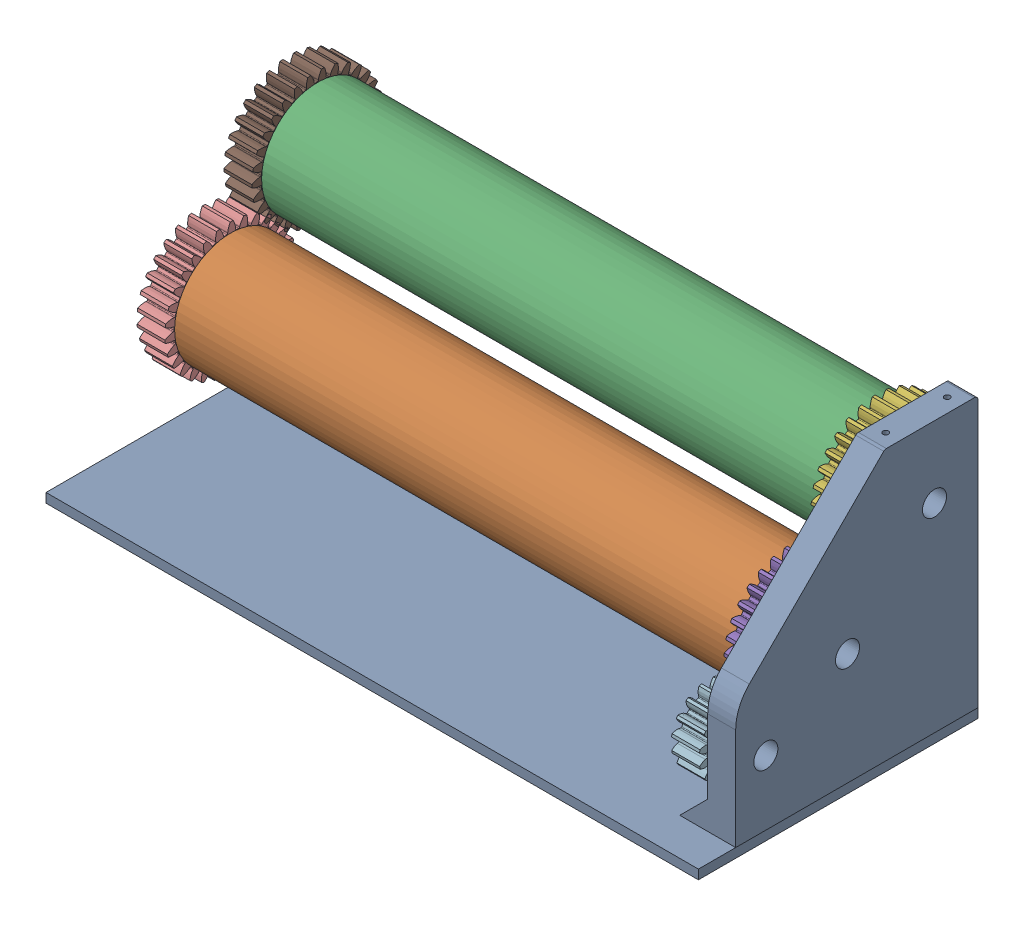
SolidWorks assembly SheetMaker, configuration Default. Lengths in mm.
Overall size (346 155.63 160.52).
13 component instances, 6 part files, 34 mates.
Components (placement in the parent):
- Base-1: Base [Default] at origin size (350 5 150) (hidden)
- Tube_60-1: Tube_60 [Default] at (-156 65 -5) x (0 -0.814129 0.580684) z (1 0 0) size (60 60 300)
- Tube_60-2: Tube_60 [Default] at (144 111.669 -51.669) x (0 -0.107637 0.99419) z (-1 0 0) size (60 60 300)
- Shaft-1: Shaft [Default] at (129 65 -5) x (0 0.66263 -0.748947) z (0 -0.748947 -0.66263) size (52 45 52)
- Gear_slave-3: Gear_slave [Default] at (151.5 65 -5) x (0 -0.979922 -0.199381) z (1 0 0) size (70.33 70.39 15)
- Gear_slave-4: Gear_slave [Default] at (151.5 111.669 -51.669) x (0 -0.821391 -0.570366) z (1 0 0) size (70.33 70.39 15)
- Shaft-2: Shaft [Default] at (129 111.669 -51.669) x (0 0.821391 0.570366) z (0 0.570366 -0.821391) size (52 45 52)
- Shaft-3: Shaft [Default] at (-141 65 -5) x (0 0.15255 -0.988296) z (0 0.988296 0.15255) size (52 45 52)
- Shaft-4: Shaft [Default] at (-141 111.669 -51.669) x (0 -0.799243 0.601008) z (0 -0.601008 -0.799243) size (52 45 52)
- Gear_slave-5: Gear_slave [Default] at (-163.5 65 -5) x (0 0.779614 0.62626) z (-1 0 0) size (70.33 70.39 15)
- Gear_slave-6: Gear_slave [Default] at (-163.5 111.669 -51.669) x (0 -0.92011 -0.391661) z (-1 0 0) size (70.33 70.39 15)
- Gear_master-3: Gear_master [Default] at (151.5 39.7 38.8209) x (0 0.997608 -0.069128) z (-1 0 0) size (39.49 39.49 15)
- Side_1-1: Side_1 [Default] at (160 5 55) x (0 0 -1) z (1 0 0) size (130 145 30)
Mates (geometry in assembly coordinates):
- Coincident2: coincident: plane of Tube_60-1 through (144 65 -5) normal (1 0 0); plane of Gear_master-1 through (165 85 52.8629) normal (-1 0 0)
- Concentric1: concentric: cylinder of Tube_60-1 through (144 65 -5) axis (-1 0 0) radius 30; circle of Gear_slave-1
- Coincident5: coincident aligned: plane of Tube_60-1 through (144 65 -5) normal (1 0 0); plane of Tube_60-2 through (144 111.669 -51.669) normal (1 0 0)
- Coincident4: coincident anti-aligned: plane of Tube_60-2 through (144 111.669 -51.669) normal (1 0 0); plane of Gear_master-2 through (165 85 -13.1371) normal (-1 0 0)
- Concentric2: concentric aligned: cylinder of Tube_60-2 through (-156 111.669 -51.669) axis (1 0 0) radius 30; circle of Gear_slave-2
- Concentric3: concentric aligned: cylinder of Tube_60-1 through (144 65 -5) axis (-1 0 0) radius 25.5; cylinder of Shaft-1 through (144 65 -5) axis (-1 0 0) radius 26
- Coincident6: coincident: line of Gear_master-1 through (165 82.8222 58.2099) axis (0 -0.613444 -0.789738); line of Shaft-1 through (144 70.4957 11.4255) axis (0 0.66263 -0.748947)
- Coincident7: coincident aligned: line of Shaft-1 through (144 48.0273 -8.4534) axis (0 0.66263 -0.748947); line of Gear_slave-3 through (144 48.0273 -8.4534) axis (0 0.66263 -0.748947)
- Coincident8: coincident aligned: line of Shaft-1 through (144 76.4771 -17.9721) axis (0 0.317292 0.948328); line of Gear_slave-3 through (144 76.4771 -17.9721) axis (0 0.317292 0.948328)
- Coincident9: coincident anti-aligned: plane of Tube_60-1 through (144 65 -5) normal (1 0 0); plane of Gear_slave-3 through (144 65 -5) normal (-1 0 0)
- Concentric4: concentric anti-aligned: cylinder of Tube_60-2 through (-156 111.669 -51.669) axis (1 0 0) radius 25.5; cylinder of Shaft-2 through (144 111.669 -51.669) axis (-1 0 0) radius 26
- Coincident10: coincident aligned: line of Gear_slave-4 through (144 96.0001 -44.2877) axis (0 0.083256 -0.996528); line of Shaft-2 through (144 96.0001 -44.2877) axis (0 0.083256 -0.996528)
- Coincident11: coincident aligned: line of Gear_slave-4 through (144 110.227 -34.4087) axis (0 -0.821391 -0.570366); line of Shaft-2 through (144 110.227 -34.4087) axis (0 -0.821391 -0.570366)
- Coincident12: coincident anti-aligned: plane of Tube_60-2 through (144 111.669 -51.669) normal (1 0 0); plane of Gear_slave-4 through (144 111.669 -51.669) normal (-1 0 0)
- Concentric5: concentric anti-aligned: cylinder of Tube_60-1 through (144 65 -5) axis (-1 0 0) radius 25.5; cylinder of Shaft-3 through (-156 65 -5) axis (1 0 0) radius 26
- Concentric6: concentric aligned: cylinder of Tube_60-2 through (-156 111.669 -51.669) axis (1 0 0) radius 25.5; cylinder of Shaft-4 through (-156 111.669 -51.669) axis (1 0 0) radius 26
- Coincident13: coincident aligned: line of Shaft-4 through (-156 127.6058 -44.8853) axis (0 -0.120867 -0.992669); line of Gear_slave-6 through (-156 127.6058 -44.8853) axis (0 -0.120867 -0.992669)
- Coincident14: coincident aligned: line of Shaft-4 through (-156 125.5123 -62.0788) axis (0 -0.92011 -0.391661); line of Gear_slave-6 through (-156 125.5123 -62.0788) axis (0 -0.92011 -0.391661)
- Coincident15: coincident aligned: line of Shaft-3 through (-156 67.6422 -22.1178) axis (0 -0.932164 0.362036); line of Gear_slave-5 through (-156 67.6422 -22.1178) axis (0 -0.932164 0.362036)
- Coincident16: coincident aligned: line of Shaft-3 through (-156 81.1456 -11.2706) axis (0 -0.779614 -0.62626); line of Gear_slave-5 through (-156 81.1456 -11.2706) axis (0 -0.779614 -0.62626)
- Coincident17: coincident anti-aligned: plane of Tube_60-1 through (-156 65 -5) normal (-1 0 0); plane of Gear_slave-5 through (-156 65 -5) normal (1 0 0)
- Coincident18: coincident anti-aligned: plane of Tube_60-2 through (-156 111.669 -51.669) normal (-1 0 0); plane of Gear_slave-6 through (-156 111.669 -51.669) normal (1 0 0)
- InPlace1: in place: plane of Base-1 through (0 5 0) normal (0 1 0); plane of ? through (0 5 0) normal (0 1 0); moOrthogonalPlaneRef_w of Base-1 through (0 5 0) normal (0 1 0); plane of ? through (0 5 0) normal (0 0 -1); plane of Base-1 through (0 5 0) normal (0 1 0); plane of ? through (0 5 0) normal (1 0 0); plane of Base-1 through (0 5 0) normal (0 1 0); unknown of ?
- Coincident20: coincident aligned: plane of Base-1; plane of ?
- Coincident21: coincident aligned: moOrthogonalPlaneRef_w of Base-1 through (0 5 0) normal (0 0 -1); plane of Part1^SheetMaker-1 through (0 5 0) normal (0 0 -1)
- Coincident22: coincident anti-aligned: moOrthogonalPlaneRef_w of Base-1 through (0 5 0) normal (-1 0 0); plane of Part1^SheetMaker-1 through (0 5 0) normal (1 0 0)
- Coincident23: coincident anti-aligned: plane of Base-1 through (0 5 0) normal (0 1 0); plane of Side_1-1 through (175 5 55) normal (0 -1 0)
- Coincident24: coincident aligned: line of Base-1 through (175 5 75) axis (0 0 -1); line of Side_1-1 through (175 5 55) axis (0 0 -1)
- Coincident25: coincident aligned: plane of Base-1 through (175 5 -75) normal (0 0 -1); plane of Side_1-1 through (175 5 -75) normal (0 0 -1)
- Concentric9: concentric anti-aligned: cylinder of Shaft-1 through (141 65 -5) axis (1 0 0) radius 3.25; cylinder of Side_1-1 through (175 65 -5) axis (-1 0 0) radius 6.45
- Distance1: distance = 1 mm anti-aligned: plane of Shaft-1 through (159 65 -5) normal (1 0 0); plane of Side_1-1 through (160 5 55) normal (-1 0 0)
- Concentric10: concentric anti-aligned: cylinder of Shaft-2 through (141 111.669 -51.669) axis (1 0 0) radius 3.25; cylinder of Side_1-1 through (175 111.669 -51.669) axis (-1 0 0) radius 6.45
- Coincident27: coincident aligned: plane of Gear_master-3 through (159 39.7 38.8209) normal (1 0 0); plane of Gear_slave-3 through (159 65 -5) normal (1 0 0)
- Concentric11: concentric anti-aligned: cylinder of Gear_master-3 through (142.8076 39.7 38.8209) axis (1 0 0) radius 3.25; cylinder of Side_1-1 through (175 39.7 38.8209) axis (-1 0 0) radius 6.45
